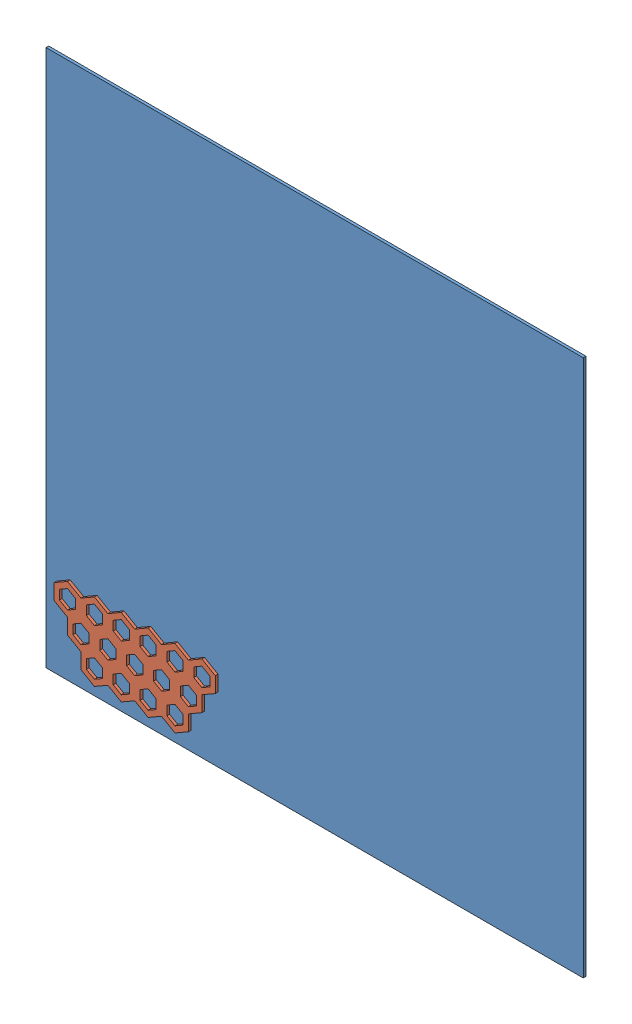
SolidWorks assembly Assem1, configuration Default. Lengths in mm.
Overall size (100 100 1).
2 component instances, 2 part files, 6 mates.
Components (placement in the parent):
- base_plate-1: base_plate [Default] at (50 50 -0.5) x (-1 0 0) z (0 1 0) size (100 0.5 100)
- honey_comb-1: honey_comb [Default] at (24.5 4.8868 0) x (-1 0 0) z (0 1 0) size (30 0.5 14.43)
Mates (geometry in assembly coordinates):
- Coincident4: coincident: point of base_plate-1
- Parallel1: parallel anti-aligned: plane of base_plate-1 through (50 50 -0.5) normal (0 0 -1)
- Parallel2: parallel anti-aligned: plane of base_plate-1 through (0 0 0) normal (0 -1 0)
- Coincident5: coincident anti-aligned: plane of base_plate-1 through (50 50 0) normal (0 0 1); plane of honey_comb-1 through (24.5 4.8868 0) normal (0 0 -1)
- Distance3: distance = 2 mm: line of honey_comb-1 through (14.5 2 0.5) axis (0 0 -1); plane of base_plate-1 through (0 0 0) normal (0 -1 0)
- Distance4: distance = 2 mm aligned: plane of honey_comb-1 through (2 4.8868 0.5) normal (-1 0 0); plane of base_plate-1 through (0 0 0) normal (-1 0 0)
